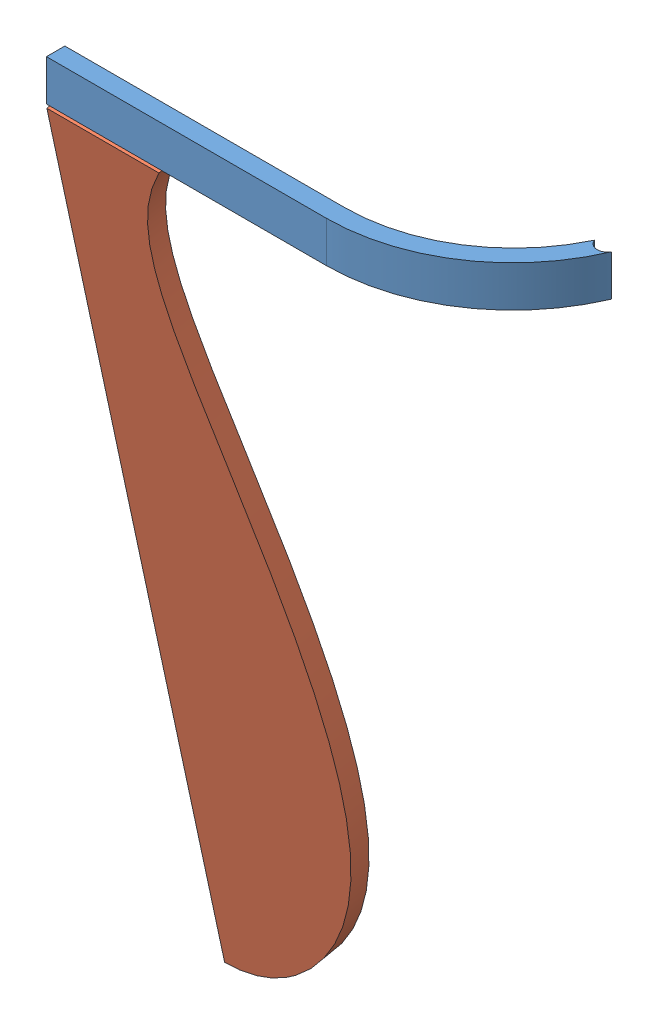
SolidWorks assembly bodysymfree, configuration Default. Lengths in mm.
Overall size (110.04 212.89 47.83).
2 component instances, 2 part files, 2 mates.
Components (placement in the parent):
- mp-1: mp [Default] at (9.9204 70.4329 1.4803) size (110.04 10 28.06)
- plade 2-1: plade 2 [Default] at (-8.8992 -20.0867 -6.2821) x (0 -0.977737 -0.209833) z (0 0.209833 -0.977737) size (206.55 46.77 4.49)
Mates (geometry in assembly coordinates):
- Coincident3: coincident aligned: line of mp-1 through (-43.5106 70.4329 8.5521) axis (1 0 0); line of plade 2-1 through (-43.5106 70.4329 8.5521) axis (1 0 0)
- Coincident4: coincident: line of mp-1 through (-43.5106 80.4329 8.5521) axis (0 -1 0); point of plade 2-1
